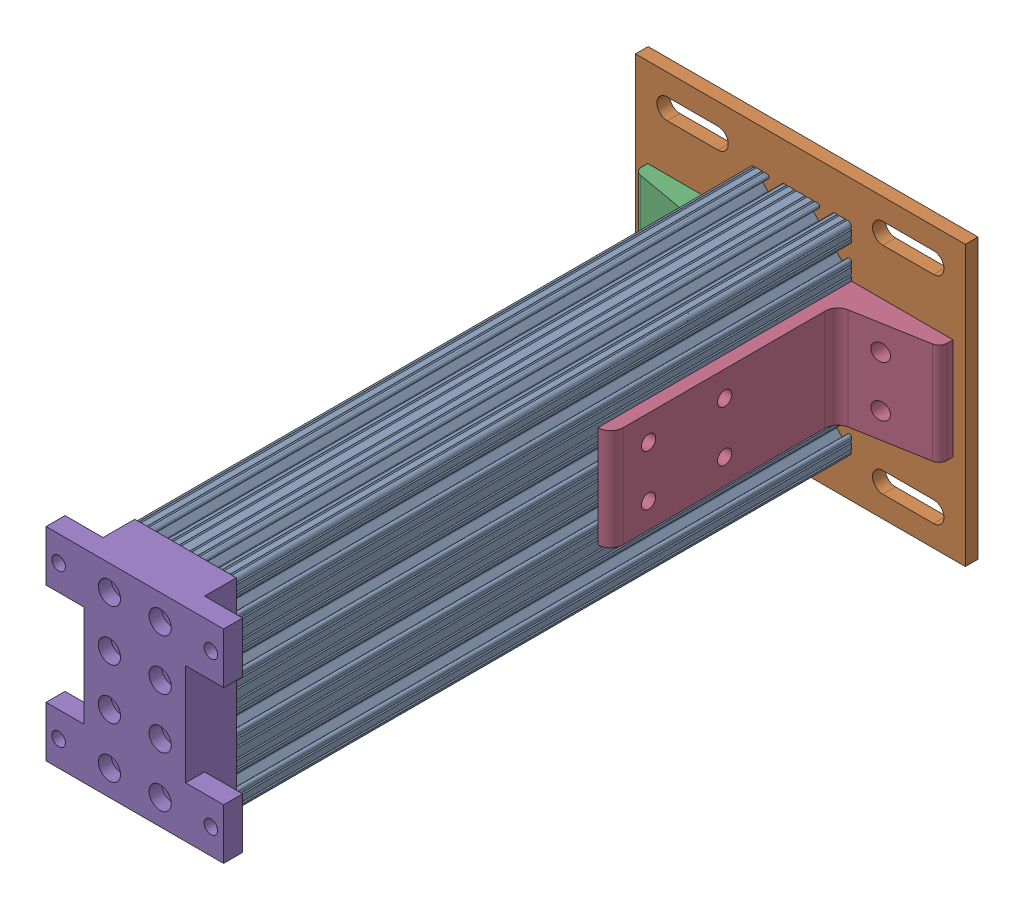
SolidWorks assembly Mirrorbreadboard support leg assembly5, configuration Default. Lengths in mm.
Overall size (165.1 139.7 339.72).
6 component instances, 4 part files, 6 mates.
Components (placement in the parent):
- Mirror8020-2040 leg for breadboard support-1: Mirror8020-2040 leg for breadboard support [Default] at (-48.9055 -77.0614 -78.1612) size (50.8 101.6 307.98)
- Mirror8020-2387-DEFAULT5-1: Mirror8020-2387-DEFAULT5 [Default] at (-34.9863 -22.6888 -91.8816) x (0 1 0) z (1 0 0) size (139.7 133.35 165.1)
  - Mirror8020-2387-DEFAULT_238708-1: Mirror8020-2387-DEFAULT_238708 [Default] at (-67.1549 7.3704 -27.8119) size (139.7 6.35 165.1)
  - Mirror8020-2387-DEFAULT_238509-1: Mirror8020-2387-DEFAULT_238509 [Default] at (9.1264 0.0214 -49.7635) x (0 0 -1) z (1 0 0) size (50.8 127 50.8)
  - Mirror8020-2387-DEFAULT_238509-2: Mirror8020-2387-DEFAULT_238509 [Default] at (-41.6736 0.0214 46.9187) x (0 0 1) z (-1 0 0) size (50.8 127 50.8)
- Mirrorbreadboard support leg top bracket-1: Mirrorbreadboard support leg top bracket [Default] at (-61.6055 -89.7614 229.8138) x (0 1 0) z (1 0 0) size (101.6 25.4 88.9)
Mates (geometry in assembly coordinates):
- Coincident1: coincident anti-aligned: plane of Mirror8020-2040 leg for breadboard support-1 through (-61.6055 -36.3198 -78.1612) normal (0 0 -1); plane of Mirror8020-2387-DEFAULT5-1/Mirror8020-2387-DEFAULT_238708-1 through (-36.4088 -207.3239 -78.1612) normal (0 0 1)
- Coincident2: coincident anti-aligned: plane of Mirror8020-2040 leg for breadboard support-1 through (-10.8056 -41.095 229.8138) normal (1 0 0); plane of Mirror8020-2387-DEFAULT5-1/Mirror8020-2387-DEFAULT_238509-2 through (-10.8056 -13.5624 -150.9329) normal (-1 0 0)
- Distance1: distance = 19.05 mm aligned: plane of Mirror8020-2387-DEFAULT5-1/Mirror8020-2387-DEFAULT_238708-1 through (-36.4088 -108.8114 -78.1612) normal (0 -1 0); plane of Mirror8020-2040 leg for breadboard support-1 through (-38.3391 -89.7614 229.8138) normal (0 -1 0)
- Coincident3: coincident anti-aligned: plane of Mirror8020-2040 leg for breadboard support-1 through (-61.6055 -36.3198 229.8138) normal (0 0 1); plane of Mirrorbreadboard support leg top bracket-1 through (-10.8055 -89.7614 229.8138) normal (0 0 -1)
- Concentric1: concentric anti-aligned: circle of Mirror8020-2040 leg for breadboard support-1; circle of Mirrorbreadboard support leg top bracket-1
- Concentric2: concentric anti-aligned: circle of Mirror8020-2040 leg for breadboard support-1; circle of Mirrorbreadboard support leg top bracket-1
